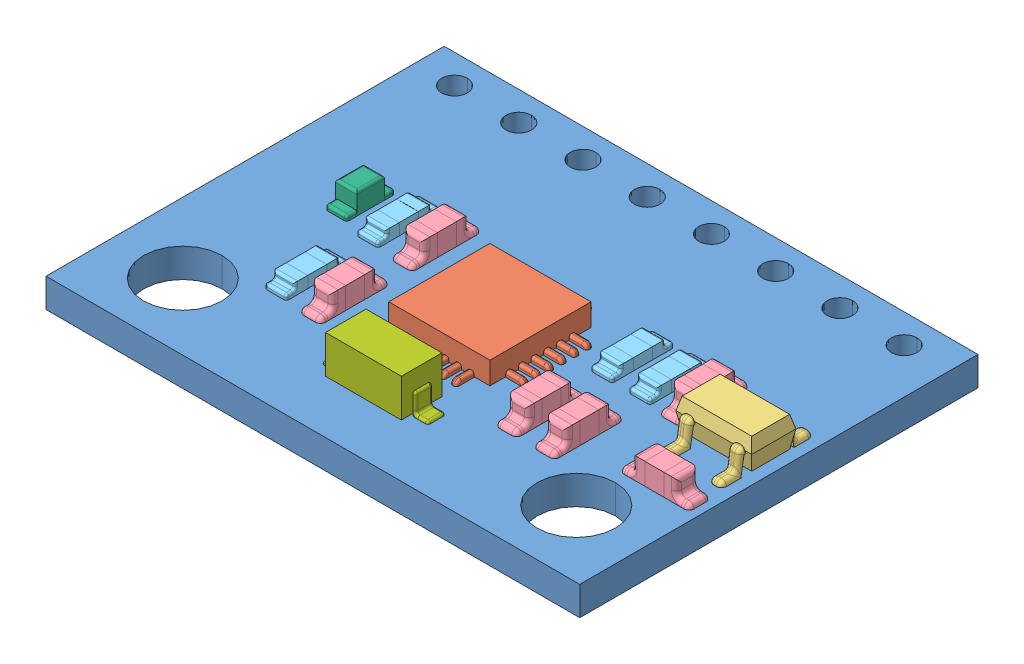
SolidWorks assembly MPU 6050 IMU.STEP, configuration Default. Lengths in mm.
Overall size (21.11 2.74 15.75).
23 component instances, 8 part files, 0 mates.
Components (placement in the parent):
- Base.STEP-1: Base.STEP [Default] at (7.2489 10.9584 16.5726) size (21.11 1.14 15.75)
- pin header.STEP-1: pin header.STEP [Default] at (16.0246 10.3869 9.8416) x (-1 0 0) z (0 0 1) size (2.54 11.18 2.54) (hidden)
- pin header.STEP-2: pin header.STEP [Default] at (13.4846 10.3869 9.8416) x (-1 0 0) z (0 0 1) size (2.54 11.18 2.54) (hidden)
- pin header.STEP-3: pin header.STEP [Default] at (10.9446 10.3869 9.8416) x (-1 0 0) z (0 0 1) size (2.54 11.18 2.54) (hidden)
- pin header.STEP-4: pin header.STEP [Default] at (8.4046 10.3869 9.8416) x (-1 0 0) z (0 0 1) size (2.54 11.18 2.54) (hidden)
- pin header.STEP-5: pin header.STEP [Default] at (5.8646 10.3869 9.8416) x (-1 0 0) z (0 0 1) size (2.54 11.18 2.54) (hidden)
- pin header.STEP-6: pin header.STEP [Default] at (3.3246 10.3869 9.8416) x (-1 0 0) z (0 0 1) size (2.54 11.18 2.54) (hidden)
- pin header.STEP-7: pin header.STEP [Default] at (0.7846 10.3869 9.8416) x (-1 0 0) z (0 0 1) size (2.54 11.18 2.54) (hidden)
- pin header.STEP-8: pin header.STEP [Default] at (-1.7554 10.3869 9.8416) x (-1 0 0) z (0 0 1) size (2.54 11.18 2.54) (hidden)
- sensor chip.STEP-1: sensor chip.STEP [Default] at (7.2489 11.5499 17.4466) size (5.4 0.9 5.4)
- S2NH chip.STEP-1: S2NH chip.STEP [Default] at (16.1026 12.3799 16.5726) size (3 1.35 3.65)
- Resistor small.STEP-1: Resistor small.STEP [Default] at (16.1026 11.5314 19.3726) size (2.75 0.94 0.95)
- Resistor small.STEP-2: Resistor small.STEP [Default] at (13.9776 11.5314 15.6976) x (0 0 -1) z (1 0 0) size (2.75 0.94 0.95)
- Resistor small black.STEP-1: Resistor small black.STEP [Default] at (12.6276 11.5299 15.6976) x (0 0 1) z (-1 0 0) size (2.45 0.54 0.95)
- Resistor small black.STEP-2: Resistor small black.STEP [Default] at (11.1276 11.5299 15.6976) x (0 0 1) z (-1 0 0) size (2.45 0.54 0.95)
- Resistor small.STEP-3: Resistor small.STEP [Default] at (12.6276 11.5314 19.3216) x (0 0 -1) z (1 0 0) size (2.75 0.94 0.95)
- Resistor small.STEP-4: Resistor small.STEP [Default] at (11.1276 11.5314 19.3216) x (0 0 -1) z (1 0 0) size (2.75 0.94 0.95)
- Resistor small.STEP-5: Resistor small.STEP [Default] at (3.3702 11.5314 19.3216) x (0 0 -1) z (1 0 0) size (2.75 0.94 0.95)
- Resistor small black.STEP-3: Resistor small black.STEP [Default] at (1.8702 11.5299 15.6968) x (0 0 -1) z (1 0 0) size (2.45 0.54 0.95)
- Resistor small.STEP-6: Resistor small.STEP [Default] at (3.3702 11.5314 15.6976) x (0 0 1) z (-1 0 0) size (2.75 0.94 0.95)
- Small LED.STEP-1: Small LED.STEP [Default] at (0.3652 11.5299 15.6976) size (0.85 0.84 1.9)
- Resistor small black.STEP-4: Resistor small black.STEP [Default] at (1.8702 11.5299 19.3216) x (0 0 1) z (-1 0 0) size (2.45 0.54 0.95)
- Resistor black.STEP-1: Resistor black.STEP [Default] at (7.2489 12.3799 21.6466) size (4.2 1.6 1.6)
